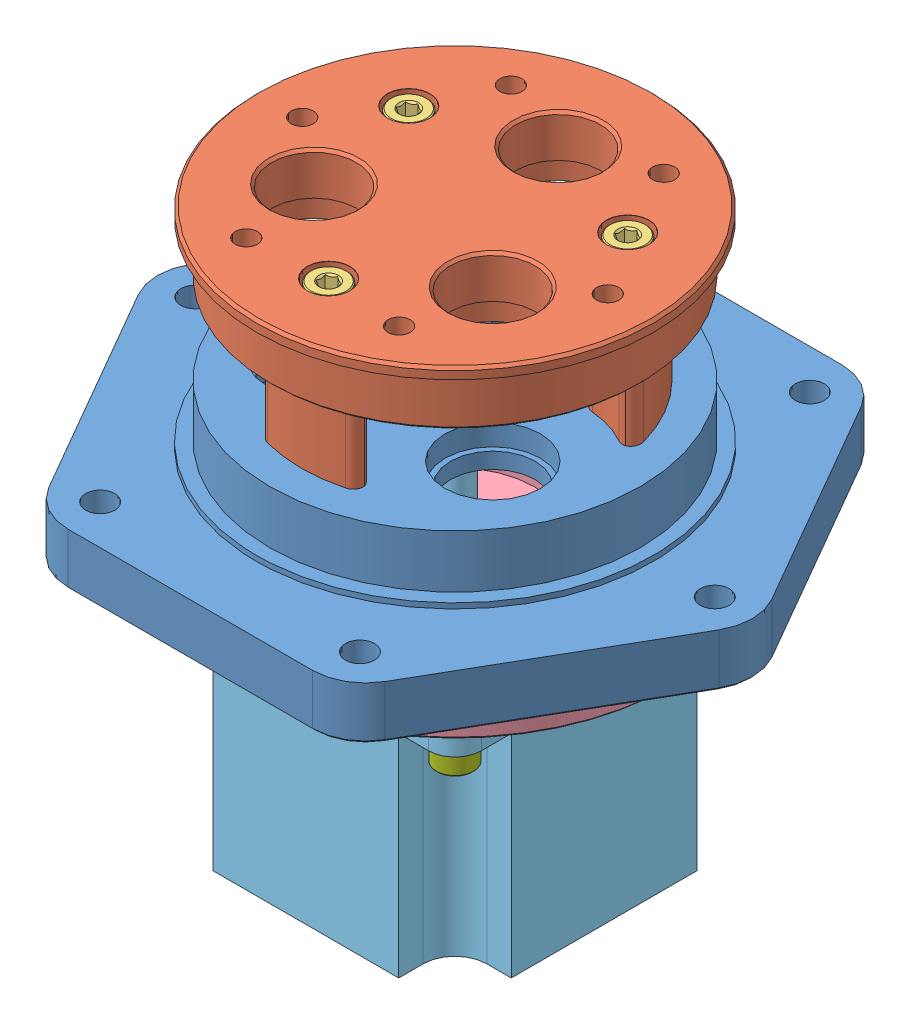
SolidWorks assembly Base Assembly, configuration Default. Lengths in mm.
Overall size (112.38 103.5 100).
19 component instances, 7 part files, 39 mates.
Components (placement in the parent):
- Base - Gear Housing-1: Base - Gear Housing [Default] at (2.343 36.5096 11.0055) size (112.38 21.91 100)
- Base - Top Cap-1: Base - Top Cap [Default] at (2.343 74.0096 11.0055) size (75 29.5 75)
- DIN912-M4x40-1: DIN912-M4x40 [91290A184] at (23.0269 63.6096 -0.9364) x (1 0 0) z (0 1 0) size (7 7 44.43)
- DIN912-M4x40-2: DIN912-M4x40 [91290A184] at (2.343 63.6096 34.8891) x (1 0 0) z (0 1 0) size (7 7 44.43)
- DIN912-M4x40-3: DIN912-M4x40 [91290A184] at (-18.3408 63.6096 -0.9364) x (1 0 0) z (0 1 0) size (7 7 44.43)
- Base - Motor Mount-1: Base - Motor Mount [Default] at (2.343 27.5096 11.0055) x (-1 0 0) z (0 0 -1) size (82 11 82)
- NEMA23 Stepper motor-1: NEMA23 Stepper motor [Default] at (2.343 -17.4904 11.0055) x (-1 0 0) z (0 0 -1) size (56.4 65 56.4)
- Heat-Set Insert - m4 5.5x6mm-1: Heat-Set Insert - m4 5.5x6mm [94459A160] at (-21.227 32.0096 -12.5645) size (6.04 6.15 6.04)
- Heat-Set Insert - m4 5.5x6mm-2: Heat-Set Insert - m4 5.5x6mm [94459A160] at (25.913 32.0096 -12.5645) size (6.04 6.15 6.04)
- Heat-Set Insert - m4 5.5x6mm-3: Heat-Set Insert - m4 5.5x6mm [94459A160] at (25.913 32.0096 34.5755) size (6.04 6.15 6.04)
- Heat-Set Insert - m4 5.5x6mm-4: Heat-Set Insert - m4 5.5x6mm [94459A160] at (-21.227 32.0096 34.5755) size (6.04 6.15 6.04)
- DIN912-M4x12-1: DIN912-M4x12 [92290A154] at (25.913 26.5096 34.5755) x (1 0 0) z (0 -1 0) size (7 7 16.25)
- DIN912-M4x12-2: DIN912-M4x12 [92290A154] at (34.843 36.7096 -2.9945) x (1 0 0) z (0 -1 0) size (7 7 16.25)
- DIN912-M4x12-3: DIN912-M4x12 [92290A154] at (-30.157 36.7096 -2.9945) x (-0.837169 0 -0.546944) z (0 -1 0) size (7 7 16.25)
- DIN912-M4x12-4: DIN912-M4x12 [92290A154] at (-10.157 36.7096 44.0055) x (1 0 0) z (0 -1 0) size (7 7 16.25)
- DIN912-M4x12-5: DIN912-M4x12 [92290A154] at (14.843 36.7096 44.0055) x (1 0 0) z (0 -1 0) size (7 7 16.25)
- DIN912-M4x12-6: DIN912-M4x12 [92290A154] at (-21.227 26.5096 34.5755) x (-0.837169 0 -0.546944) z (0 -1 0) size (7 7 16.25)
- DIN912-M4x12-7: DIN912-M4x12 [92290A154] at (25.913 26.5096 -12.5645) x (1 0 0) z (0 -1 0) size (7 7 16.25)
- DIN912-M4x12-8: DIN912-M4x12 [92290A154] at (-21.227 26.5096 -12.5645) x (1 0 0) z (0 -1 0) size (7 7 16.25)
Mates (geometry in assembly coordinates):
- Coincident47: coincident anti-aligned: plane of Base - Gear Housing-1 through (2.343 57.5096 11.0055) normal (0 1 0); plane of Base - Top Cap-1 through (2.343 57.5096 11.0055) normal (0 -1 0)
- Concentric71: concentric anti-aligned: cylinder of Base - Top Cap-1 through (23.0269 86.0096 -0.9364) axis (0 1 0) radius 2.25; cylinder of DIN912-M4x40-1 through (23.0269 41.6096 -0.9364) axis (0 -1 0) radius 2.0758
- Coincident53: coincident anti-aligned: plane of Base - Top Cap-1 through (27.0269 81.6096 -0.9364) normal (0 1 0); plane of DIN912-M4x40-1 through (23.0269 81.6096 -4.2364) normal (0 -1 0)
- Concentric72: concentric anti-aligned: cylinder of Base - Top Cap-1 through (-18.3408 86.0096 -0.9364) axis (0 1 0) radius 2.25; cylinder of DIN912-M4x40-3 through (-18.3408 41.6096 -0.9364) axis (0 -1 0) radius 2.0758
- Concentric73: concentric anti-aligned: cylinder of Base - Top Cap-1 through (2.343 86.0096 34.8891) axis (0 1 0) radius 2.25; cylinder of DIN912-M4x40-2 through (2.343 41.6096 34.8891) axis (0 -1 0) radius 2.0758
- Coincident54: coincident anti-aligned: plane of Base - Top Cap-1 through (-14.3408 81.6096 -0.9364) normal (0 1 0); plane of DIN912-M4x40-3 through (-18.3408 81.6096 -4.2364) normal (0 -1 0)
- Coincident55: coincident anti-aligned: plane of Base - Top Cap-1 through (6.343 81.6096 34.8891) normal (0 1 0); plane of DIN912-M4x40-2 through (2.343 81.6096 31.5891) normal (0 -1 0)
- Coincident27: coincident anti-aligned: plane of Base - Motor Mount-1 through (2.343 27.5096 11.0055) normal (0 -1 0); plane of nema21 motor-1 through (25.543 27.5096 -12.1945) normal (0 1 0)
- Concentric36: concentric aligned: cylinder of nema21 motor-1 through (25.913 27.5096 -12.5645) axis (0 -1 0) radius 2.5; cylinder of Base - Motor Mount-1 through (25.913 36.5096 -12.5645) axis (0 -1 0) radius 2.15
- Concentric37: concentric aligned: cylinder of nema21 motor-1 through (-21.227 27.5096 34.5755) axis (0 -1 0) radius 2.5; cylinder of Base - Motor Mount-1 through (-21.227 36.5096 34.5755) axis (0 -1 0) radius 2.15
- Concentric75: concentric anti-aligned: cylinder of Base - Gear Housing-1 through (-14.5444 82.9654 20.7555) axis (0 -1 0) radius 8; cylinder of Base - Top Cap-1 through (-14.5444 48.5538 20.7555) axis (0 1 0) radius 8
- Concentric76: concentric anti-aligned: cylinder of Base - Gear Housing-1 through (2.343 82.9654 -8.4945) axis (0 -1 0) radius 8; cylinder of Base - Top Cap-1 through (2.343 48.5538 -8.4945) axis (0 1 0) radius 8
- Parallel1: parallel aligned: plane of Base - Gear Housing-1 through (-26.5245 199.2621 -38.9945) normal (0 0 -1); plane of nema21 motor-1 through (25.543 27.5096 -17.1945) normal (0 0 -1)
- Coincident57: coincident anti-aligned: plane of Base - Gear Housing-1 through (2.343 36.5096 11.0055) normal (0 -1 0); plane of Base - Motor Mount-1 through (2.343 36.5096 11.0055) normal (0 1 0)
- Coincident79: coincident anti-aligned: plane of Base - Motor Mount-1 through (-21.227 29.0096 -12.5645) normal (0 1 0); plane of Heat-Set Insert - m4 5.5x6mm-1 through (-18.477 29.0096 -12.5645) normal (0 -1 0)
- Concentric92: concentric anti-aligned: cylinder of Base - Motor Mount-1 through (-21.227 29.0096 -12.5645) axis (0 1 0) radius 2.75; cylinder of Heat-Set Insert - m4 5.5x6mm-1 through (-21.227 29.0096 -12.5645) axis (0 -1 0) radius 2.75
- Coincident78: coincident anti-aligned: plane of Base - Motor Mount-1 through (25.913 29.0096 -12.5645) normal (0 1 0); plane of Heat-Set Insert - m4 5.5x6mm-2 through (28.663 29.0096 -12.5645) normal (0 -1 0)
- Concentric93: concentric anti-aligned: cylinder of Base - Motor Mount-1 through (25.913 29.0096 -12.5645) axis (0 1 0) radius 2.75; cylinder of Heat-Set Insert - m4 5.5x6mm-2 through (25.913 29.0096 -12.5645) axis (0 -1 0) radius 2.75
- Coincident76: coincident anti-aligned: plane of Base - Motor Mount-1 through (25.913 29.0096 34.5755) normal (0 1 0); plane of Heat-Set Insert - m4 5.5x6mm-3 through (28.663 29.0096 34.5755) normal (0 -1 0)
- Concentric94: concentric anti-aligned: cylinder of Base - Motor Mount-1 through (25.913 29.0096 34.5755) axis (0 1 0) radius 2.75; cylinder of Heat-Set Insert - m4 5.5x6mm-3 through (25.913 29.0096 34.5755) axis (0 -1 0) radius 2.75
- Coincident77: coincident anti-aligned: plane of Base - Motor Mount-1 through (-21.227 29.0096 34.5755) normal (0 1 0); plane of Heat-Set Insert - m4 5.5x6mm-4 through (-18.477 29.0096 34.5755) normal (0 -1 0)
- Concentric95: concentric anti-aligned: cylinder of Base - Motor Mount-1 through (-21.227 29.0096 34.5755) axis (0 1 0) radius 2.75; cylinder of Heat-Set Insert - m4 5.5x6mm-4 through (-21.227 29.0096 34.5755) axis (0 -1 0) radius 2.75
- Coincident86: coincident anti-aligned: plane of NEMA23 Stepper motor-1 through (25.543 22.5096 -12.1945) normal (0 -1 0); plane of DIN912-M4x12-1 through (25.913 22.5096 36.5755) normal (0 1 0)
- Concentric101: concentric aligned: cylinder of NEMA23 Stepper motor-1 through (25.913 27.5096 34.5755) axis (0 -1 0) radius 2.5; cylinder of DIN912-M4x12-1 through (25.913 18.5096 34.5755) axis (0 -1 0) radius 3.5
- Coincident83: coincident anti-aligned: plane of Base - Motor Mount-1 through (30.843 32.7096 -2.9945) normal (0 -1 0); plane of DIN912-M4x12-2 through (34.843 32.7096 -0.9945) normal (0 1 0)
- Concentric99: concentric aligned: cylinder of Base - Motor Mount-1 through (34.843 27.5096 -2.9945) axis (0 -1 0) radius 4; cylinder of DIN912-M4x12-2 through (34.843 28.7096 -2.9945) axis (0 -1 0) radius 3.5
- Concentric98: concentric aligned: cylinder of Base - Motor Mount-1 through (-30.157 27.5096 -2.9945) axis (0 -1 0) radius 4; cylinder of DIN912-M4x12-3 through (-30.157 28.7096 -2.9945) axis (0 -1 0) radius 3.5
- Coincident82: coincident anti-aligned: plane of Base - Motor Mount-1 through (-34.157 32.7096 -2.9945) normal (0 -1 0); plane of DIN912-M4x12-3 through (-29.0631 32.7096 -4.6689) normal (0 1 0)
- Coincident80: coincident anti-aligned: plane of Base - Motor Mount-1 through (-14.157 32.7096 44.0055) normal (0 -1 0); plane of DIN912-M4x12-4 through (-10.157 32.7096 46.0055) normal (0 1 0)
- Concentric97: concentric aligned: cylinder of Base - Motor Mount-1 through (-10.157 27.5096 44.0055) axis (0 -1 0) radius 4; cylinder of DIN912-M4x12-4 through (-10.157 28.7096 44.0055) axis (0 -1 0) radius 3.5
- Coincident81: coincident anti-aligned: plane of Base - Motor Mount-1 through (10.843 32.7096 44.0055) normal (0 -1 0); plane of DIN912-M4x12-5 through (14.843 32.7096 46.0055) normal (0 1 0)
- Concentric96: concentric aligned: cylinder of Base - Motor Mount-1 through (14.843 27.5096 44.0055) axis (0 -1 0) radius 4; cylinder of DIN912-M4x12-5 through (14.843 28.7096 44.0055) axis (0 -1 0) radius 3.5
- Concentric102: concentric aligned: cylinder of NEMA23 Stepper motor-1 through (-21.227 27.5096 34.5755) axis (0 -1 0) radius 2.5; cylinder of DIN912-M4x12-6 through (-21.227 18.5096 34.5755) axis (0 -1 0) radius 3.5
- Coincident87: coincident anti-aligned: plane of NEMA23 Stepper motor-1 through (25.543 22.5096 -12.1945) normal (0 -1 0); plane of DIN912-M4x12-6 through (-20.1331 22.5096 32.9011) normal (0 1 0)
- Coincident85: coincident anti-aligned: plane of NEMA23 Stepper motor-1 through (25.543 22.5096 -12.1945) normal (0 -1 0); plane of DIN912-M4x12-7 through (25.913 22.5096 -10.5645) normal (0 1 0)
- Concentric100: concentric aligned: cylinder of NEMA23 Stepper motor-1 through (25.913 27.5096 -12.5645) axis (0 -1 0) radius 2.5; cylinder of DIN912-M4x12-7 through (25.913 18.5096 -12.5645) axis (0 -1 0) radius 3.5
- Coincident88: coincident anti-aligned: plane of NEMA23 Stepper motor-1 through (25.543 22.5096 -12.1945) normal (0 -1 0); plane of DIN912-M4x12-8 through (-21.227 22.5096 -10.5645) normal (0 1 0)
- Concentric103: concentric aligned: cylinder of NEMA23 Stepper motor-1 through (-21.227 27.5096 -12.5645) axis (0 -1 0) radius 2.5; cylinder of DIN912-M4x12-8 through (-21.227 18.5096 -12.5645) axis (0 -1 0) radius 3.5
- Concentric105: concentric anti-aligned: circle of Base - Gear Housing-1; circle of Base - Motor Mount-1
